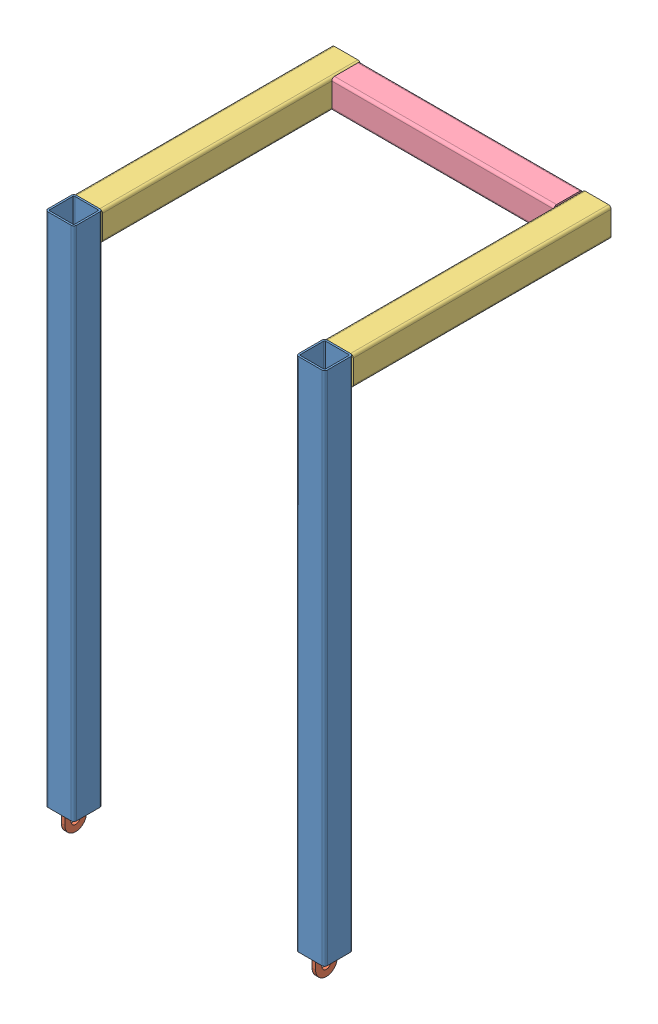
SolidWorks assembly Log Lift Assb, configuration Default. Lengths in mm.
Overall size (495.3 952.5 508).
7 component instances, 4 part files, 16 mates.
Components (placement in the parent):
- Log Lift Vertical-1: Log Lift Vertical [Default] at (209.9031 402.3815 621.0169) size (50.8 914.4 50.8)
- Log Lift Vertical-2: Log Lift Vertical [Default] at (654.4031 402.3815 621.0169) size (50.8 914.4 50.8)
- Log Lift Clevis-1: Log Lift Clevis [Default] at (209.9031 -73.8685 621.0169) x (-1 0 0) z (0 0 1) size (6.35 38.1 38.1)
- Log Lift Clevis-2: Log Lift Clevis [Default] at (654.4031 -73.8685 621.0169) x (-1 0 0) z (0 0 1) size (6.35 38.1 38.1)
- Log Lift Horz-1: Log Lift Horz [Default] at (209.9031 834.1815 367.0169) size (50.8 50.8 457.2)
- Log Lift Horz-2: Log Lift Horz [Default] at (654.4031 834.1815 367.0169) size (50.8 50.8 457.2)
- Log Lift Front-1: Log Lift Front [Default] at (432.1531 834.1815 163.8169) size (393.7 50.8 50.8)
Mates (geometry in assembly coordinates):
- Coincident1: coincident aligned: line of Log Lift Vertical-1 through (209.9031 -54.8185 646.4169) axis (0 0 -1); line of Log Lift Clevis-1 through (209.9031 -54.8185 640.0669) axis (0 0 -1)
- Coincident2: coincident anti-aligned: line of Log Lift Vertical-1 through (184.5031 -54.8185 621.0169) axis (1 0 0); line of Log Lift Clevis-1 through (213.0781 -54.8185 621.0169) axis (-1 0 0)
- Coincident3: coincident aligned: line of Log Lift Vertical-2 through (654.4031 -54.8185 646.4169) axis (0 0 -1); line of Log Lift Clevis-2 through (654.4031 -54.8185 640.0669) axis (0 0 -1)
- Coincident4: coincident anti-aligned: line of Log Lift Vertical-2 through (629.0031 -54.8185 621.0169) axis (1 0 0); line of Log Lift Clevis-2 through (657.5781 -54.8185 621.0169) axis (-1 0 0)
- Coincident5: coincident aligned: plane of Log Lift Vertical-1 through (230.5406 859.5815 641.6544) normal (0 1 0); plane of Log Lift Horz-1 through (189.2656 859.5815 595.6169) normal (0 1 0)
- Coincident6: coincident aligned: plane of Log Lift Vertical-1 through (235.3031 859.5815 641.6544) normal (1 0 0); plane of Log Lift Horz-1 through (235.3031 813.544 595.6169) normal (1 0 0)
- Coincident7: coincident aligned: plane of Log Lift Vertical-2 through (675.0406 859.5815 641.6544) normal (0 1 0); plane of Log Lift Horz-2 through (633.7656 859.5815 595.6169) normal (0 1 0)
- Coincident8: coincident aligned: plane of Log Lift Vertical-2 through (679.8031 859.5815 641.6544) normal (1 0 0); plane of Log Lift Horz-2 through (679.8031 813.544 595.6169) normal (1 0 0)
- Coincident9: coincident anti-aligned: plane of Log Lift Vertical-2 through (633.7656 859.5815 595.6169) normal (0 0 -1); plane of Log Lift Horz-2 through (675.0406 813.544 595.6169) normal (0 0 1)
- Coincident10: coincident anti-aligned: plane of Log Lift Vertical-1 through (189.2656 859.5815 595.6169) normal (0 0 -1); plane of Log Lift Horz-1 through (230.5406 813.544 595.6169) normal (0 0 1)
- Coincident11: coincident aligned: plane of Log Lift Horz-1 through (189.2656 859.5815 595.6169) normal (0 1 0); plane of Log Lift Front-1 through (629.0031 859.5815 184.4544) normal (0 1 0)
- Coincident12: coincident aligned: plane of Log Lift Horz-1 through (230.5406 813.544 138.4169) normal (0 0 -1); plane of Log Lift Front-1 through (629.0031 813.544 138.4169) normal (0 0 -1)
- Coincident13: coincident anti-aligned: plane of Log Lift Horz-1 through (235.3031 813.544 595.6169) normal (1 0 0); plane of Log Lift Front-1 through (235.3031 813.544 143.1794) normal (-1 0 0)
- Coincident14: coincident anti-aligned: plane of Log Lift Horz-2 through (629.0031 813.544 595.6169) normal (-1 0 0); plane of Log Lift Front-1 through (629.0031 813.544 143.1794) normal (1 0 0)
- Coincident15: coincident aligned: plane of Log Lift Horz-2 through (675.0406 813.544 138.4169) normal (0 0 -1); plane of Log Lift Front-1 through (629.0031 813.544 138.4169) normal (0 0 -1)
- Coincident16: coincident aligned: plane of Log Lift Horz-2 through (633.7656 859.5815 595.6169) normal (0 1 0); plane of Log Lift Front-1 through (629.0031 859.5815 184.4544) normal (0 1 0)
